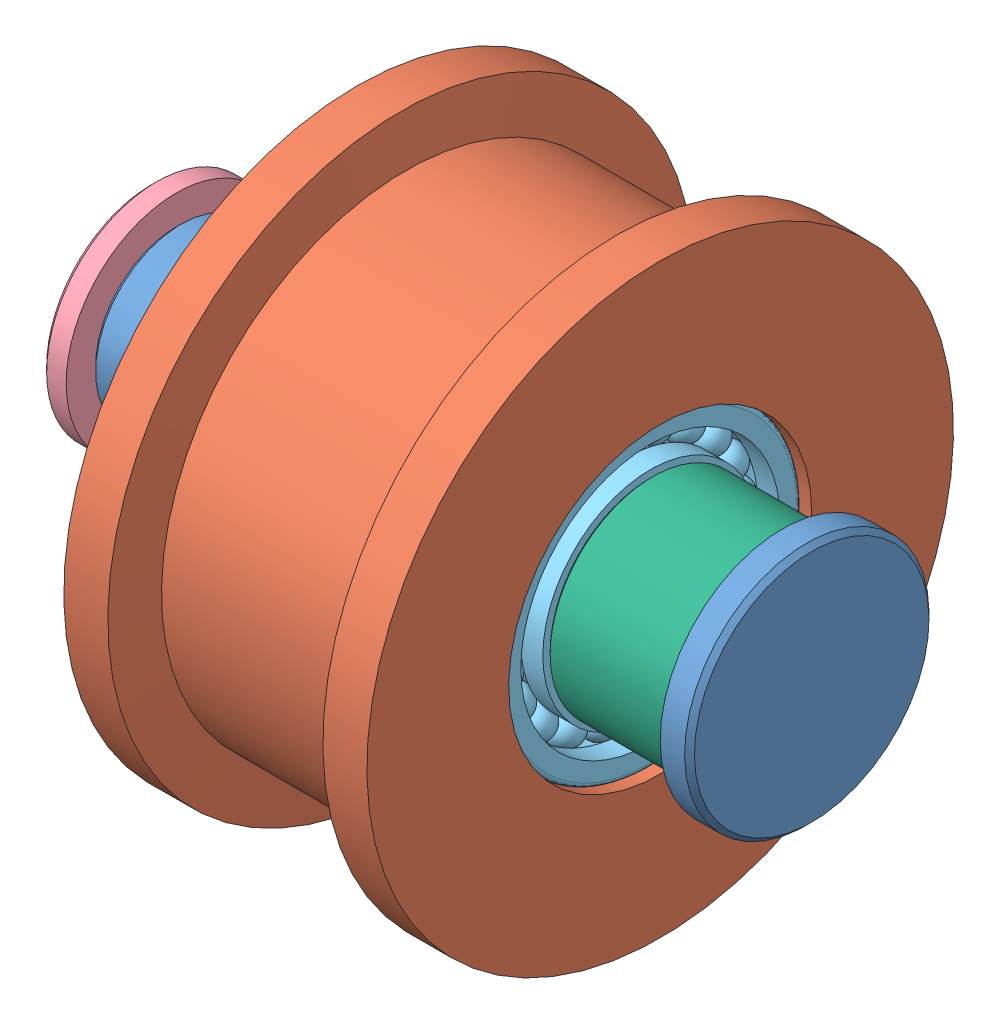
SolidWorks assembly 中臂托轮装配1, configuration 默认. Lengths in mm.
Overall size (135 126.08 126.08).
7 component instances, 6 part files, 19 mates.
Components (placement in the parent):
- 中臂托轮轴1-2: 中臂托轮轴1 [默认] at (-10878.6909 -1498.5339 2962.1158) x (-1 0 0) z (0 0.924225 0.381849) size (130 50 50)
- 中臂托轮-2: 中臂托轮 [默认] at (-10876.4278 1717.8901 -11294.0292) x (0 -0.998648 -0.051983) z (1 0 0) size (120 120 62)
- 中臂托轮挡圈-3: 中臂托轮挡圈 [默认] at (-6697.2675 1333.2526 -3968.4491) size (27 42 42)
- GB T892 B30挡圈-1: GB T892 B30挡圈 [默认] at (-6772.5125 1332.4905 -3890.0698) x (-1 0 0) z (0 -0.924225 -0.381849) size (5 45 45)
- deep groove ball bearings gb-3: deep groove ball bearings gb [Rolling bearings 6007 GB 276-94] at (-6682.5125 1332.4905 -3890.0698) size (14 62 62)
- deep groove ball bearings gb-4: deep groove ball bearings gb [Rolling bearings 6007 GB 276-94] at (-6726.5125 1332.4905 -3890.0698) size (14 62 62)
- 轴套35-1: 轴套35 [Default] at (-6675.5125 1332.4905 -3890.0698) size (28 42 42)
Mates (geometry in assembly coordinates):
- 重合1: coincident: plane of ? through (-6733.0125 1359.9905 -3890.0698) normal (1 0 0); plane of 中臂托轮-2 through (-6733.0125 1330.8791 -3859.1117) normal (-1 0 0)
- 重合2: coincident: plane of ? through (-6703.0125 1395.2641 -3919.161) normal (-1 0 0); plane of 中臂托轮-2 through (-6703.0125 1366.1526 -3888.2029) normal (1 0 0)
- 同心1: concentric: cylinder of ? through (-6707.2232 1367.7641 -3919.161) axis (-1 0 0) radius 27.5; cylinder of 中臂托轮-2 through (-6654.7494 1367.7641 -3919.161) axis (1 0 0) radius 35
- 同心3: concentric: cylinder of ? through (-6746.2232 1332.4905 -3890.0698) axis (-1 0 0) radius 27.5; cylinder of 中臂托轮-2 through (-6654.7494 1332.4905 -3890.0698) axis (1 0 0) radius 31
- 同心4: concentric: cylinder of 中臂托轮轴1-2 through (-6665.4723 1332.4905 -3890.0698) axis (1 0 0) radius 15; cylinder of ? through (-6744.4839 1332.4905 -3890.0698) axis (-1 0 0) radius 15
- 重合7: coincident: plane of 中臂托轮轴1-2 through (-6694.0125 1360.1271 -3900.6765) normal (-1 0 0); plane of ? through (-6694.0125 1382.7641 -3919.161) normal (1 0 0)
- 同心5: concentric: cylinder of 中臂托轮轴1-2 through (-6662.9723 1332.4905 -3890.0698) axis (1 0 0) radius 17.5; cylinder of 中臂托轮挡圈-3 through (-6850.6434 1332.4905 -3890.0698) axis (-1 0 0) radius 18
- 重合8: coincident: plane of ? through (-6742.0125 1351.6572 -3890.0698) normal (-1 0 0); plane of 中臂托轮挡圈-3 through (-6742.0125 1332.4285 -3909.0697) normal (1 0 0)
- 重合9: coincident: plane of 中臂托轮轴1-2 through (-6772.5125 1326.19 -3874.8201) normal (-1 0 0); plane of GB T892 B30挡圈-1 through (-6772.5125 1332.4905 -3890.0698) normal (1 0 0)
- 同心6: concentric: cylinder of 中臂托轮轴1-2 through (-6772.5125 1332.4905 -3890.0698) axis (-1 0 0) radius 2.5; cylinder of GB T892 B30挡圈-1 through (-6777.5125 1332.4905 -3890.0698) axis (1 0 0) radius 3.3
- 同心7: concentric: cylinder of 中臂托轮-2 through (-6641.2494 1332.4905 -3890.0698) axis (1 0 0) radius 31; cylinder of deep groove ball bearings gb-3 through (-6691.2232 1332.4905 -3890.0698) axis (-1 0 0) radius 31
- 重合10: coincident: plane of 中臂托轮-2 through (-6689.5125 1331.087 -3863.1063) normal (1 0 0); plane of deep groove ball bearings gb-3 through (-6689.5125 1363.4905 -3890.0698) normal (-1 0 0)
- 同心8: concentric: cylinder of 中臂托轮轴1-2 through (-6662.9723 1332.4905 -3890.0698) axis (1 0 0) radius 17.5; cylinder of deep groove ball bearings gb-3 through (-6689.4839 1332.4905 -3890.0698) axis (-1 0 0) radius 17.5
- 同心9: concentric: cylinder of 中臂托轮-2 through (-6641.2494 1332.4905 -3890.0698) axis (1 0 0) radius 31; cylinder of deep groove ball bearings gb-4 through (-6735.2232 1332.4905 -3890.0698) axis (-1 0 0) radius 31
- 重合11: coincident: plane of 中臂托轮-2 through (-6719.5125 1330.8791 -3859.1117) normal (-1 0 0); plane of deep groove ball bearings gb-4 through (-6719.5125 1363.4905 -3890.0698) normal (1 0 0)
- 重合12: coincident: plane of 中臂托轮挡圈-3 through (-6733.5125 1332.422 -3911.0697) normal (1 0 0); plane of deep groove ball bearings gb-4 through (-6733.5125 1354.4905 -3890.0698) normal (-1 0 0)
- 距离1: distance = 12 mm: plane of GB T892 B30挡圈-1 through (-6772.5125 1332.4905 -3890.0698) normal (1 0 0); plane of 中臂托轮挡圈-3 through (-6760.5125 1332.422 -3911.0697) normal (-1 0 0)
- 同心10: concentric: cylinder of 中臂托轮轴1-2 through (-6662.9723 1332.4905 -3890.0698) axis (1 0 0) radius 17.5; cylinder of 轴套35-1 through (-6647.5125 1332.4905 -3890.0698) axis (-1 0 0) radius 18
- 重合13: coincident: plane of deep groove ball bearings gb-3 through (-6675.5125 1349.9905 -3890.0698) normal (1 0 0); plane of 轴套35-1 through (-6675.5125 1332.4905 -3890.0698) normal (-1 0 0)
